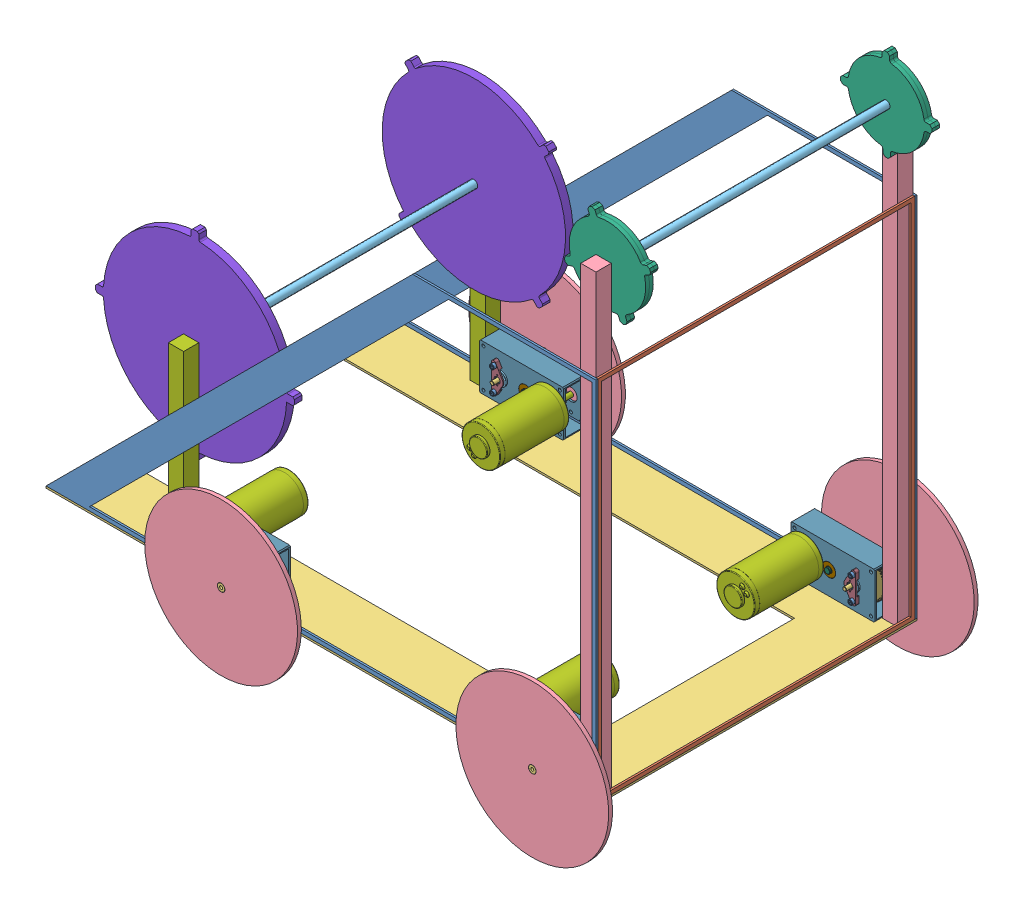
SolidWorks assembly catbot, configuration Default. Lengths in mm.
Overall size (1017.77 943.44 617.22).
104 component instances, 26 part files, 65 mates.
Components (placement in the parent):
- out frame-1: out frame [Default] at (-229.7492 222.8488 726.0954) size (914.4 609.6 3.17)
- out frame-2: out frame [Default] at (-229.7492 222.8488 1256.3204) size (914.4 609.6 3.17)
- front outer chassis-1: front outer chassis [Default] at (684.6508 527.6488 992.7954) x (0 0 1) z (-1 0 0) size (527.05 609.6 3.17)
- base plate-1: base plate [Default] at (227.4508 219.6738 992.7954) x (-1 0 0) z (0 0 -1) size (914.4 3.17 533.4)
- bar-1: bar [Default] at (644.4149 984.8488 731.8104) x (1 0 0) z (0 -1 0) size (25.4 25.4 762)
- bar-2: bar [Default] at (644.4149 222.8488 1253.7804) x (1 0 0) z (0 1 0) size (25.4 25.4 762)
- Toughbox Nano 500 key-1: Toughbox Nano 500 key [Default] at (-4.173 260.9488 745.1454) x (1 0 0) z (0 -1 0) size (155.61 199.38 84.31)
  - fr-6-zz-1: fr-6-zz [Default] at (44.2691 14.351 6.042) x (1 0 0) z (0 1 0) size (24.69 24.69 7.16)
  - fr8zz-hex-1: fr8zz-hex [Default] at (35.4076 -22.2783 0) x (0.98361 0 -0.180311) z (0 1 0) size (31.12 31.12 7.93)
  - CIM motor-1: CIM motor [Default] at (226.1362 38.1 -35.56) x (0 0 1) z (0 -1 0) size (64.01 64.01 154.95)
  - fr-6-zz-hex-1: fr-6-zz-hex [Default] at (84.883 -14.351 -6.1894) x (0.99986 0 -0.016728) z (0 -1 0) size (24.69 24.69 7.75)
  - fr-6-1: fr-6 [Default] at (86.7029 13.5128 -1.7646) x (0.722285 0 -0.691595) z (0 1 0) size (24.69 24.69 5.54)
  - Toughbox_d05-1: Toughbox_d05 [Default] at (76.1238 3.3528 0) x (-0.016728 0 -0.99986) z (0 1 0) size (65.97 66.04 10.34)
  - Toughbox_d08-1: Toughbox_d08 [Default] at (76.1238 3.3528 0) x (0.874268 0 0.485443) z (0 -1 0) size (20.03 20.32 15.25)
  - Toughbox_d06-1: Toughbox_d06 [Default] at (35.4076 -0.4318 0) x (0.335651 0 -0.941987) z (0 -1 0) size (65.97 66.04 10.62)
  - Toughbox_d29a-1: Toughbox_d29a [Default] at (35.3949 19.05 0) size (19.05 6.1 50.8)
  - Toughbox-nano-d01-1: Toughbox-nano-d01 [Default] at origin size (139.7 38.1 76.2)
  - Toughbox-nano-d02-1: Toughbox-nano-d02 [Default] at (33.7409 -21.4122 -4.4704) x (-0.874268 0 -0.485443) z (-0.485443 0 0.874268) size (11 43.81 9.52)
  - Toughbox_d09-1: Toughbox_d09 [Default] at (116.84 1.524 0) x (-1 0 0) z (0 1 0) size (20.03 20.32 12.7)
  - 8mm_spring_clip-1: 8mm_spring_clip [Default] at (116.84 0.5836 0) x (0 1 0) z (0.466354 0 -0.884598) size (1.12 14.83 14.83)
  - 2mmx2mmx10mm_key-1: 2mmx2mmx10mm_key [Default] at (119.2442 -2.476 4.8) x (0 1 0) z (1 0 0) size (10 2 2)
  - 10-32x0500_shcs-1: 10-32x0500_shcs [Default] at (30.6324 29.9212 19.05) x (0.282005 0 -0.959413) z (0.959413 0 0.282005) size (7.82 17.48 7.82)
  - 10-32x0500_shcs-2: 10-32x0500_shcs [Default] at (30.6324 29.9212 -19.05) x (0.282005 0 -0.959413) z (0.959413 0 0.282005) size (7.82 17.48 7.82)
  - 10-32x0500_shcs-3: 10-32x0500_shcs [Default] at (116.84 11.0998 -25.4) x (-0.525528 0 0.850777) z (0.850777 0 0.525528) size (7.82 17.48 7.82)
  - 10-32x0500_shcs-4: 10-32x0500_shcs [Default] at (116.84 11.0998 25.4) x (-0.525528 0 0.850777) z (0.850777 0 0.525528) size (7.82 17.48 7.82)
  - 500-e-klip-1: 500-e-klip [Default] at (35.4076 0.8382 0) x (-0.210896 0 -0.977509) z (0 -1 0) size (19.07 20.96 1.27)
  - Toughbox-nano-d04-1: Toughbox-nano-d04 [Default] at (-2.1102 -22.352 -18.3768) x (-0.647959 0 -0.761675) z (-0.761675 0 0.647959) size (14.66 95.12 12.7)
- Toughbox Nano 500 key-2: Toughbox Nano 500 key [Default] at (135.527 260.9488 1237.2704) x (-1 0 0) z (0 -1 0) size (155.61 199.38 84.31)
  - fr-6-zz-1: fr-6-zz [Default] at (44.2691 14.351 6.042) x (1 0 0) z (0 1 0) size (24.69 24.69 7.16)
  - fr8zz-hex-1: fr8zz-hex [Default] at (35.4076 -22.2783 0) x (0.98361 0 -0.180311) z (0 1 0) size (31.12 31.12 7.93)
  - CIM motor-1: CIM motor [Default] at (226.1362 38.1 -35.56) x (0 0 1) z (0 -1 0) size (64.01 64.01 154.95)
  - fr-6-zz-hex-1: fr-6-zz-hex [Default] at (84.883 -14.351 -6.1894) x (0.99986 0 -0.016728) z (0 -1 0) size (24.69 24.69 7.75)
  - fr-6-1: fr-6 [Default] at (86.7029 13.5128 -1.7646) x (0.722285 0 -0.691595) z (0 1 0) size (24.69 24.69 5.54)
  - Toughbox_d05-1: Toughbox_d05 [Default] at (76.1238 3.3528 0) x (-0.016728 0 -0.99986) z (0 1 0) size (65.97 66.04 10.34)
  - Toughbox_d08-1: Toughbox_d08 [Default] at (76.1238 3.3528 0) x (0.874268 0 0.485443) z (0 -1 0) size (20.03 20.32 15.25)
  - Toughbox_d06-1: Toughbox_d06 [Default] at (35.4076 -0.4318 0) x (0.335651 0 -0.941987) z (0 -1 0) size (65.97 66.04 10.62)
  - Toughbox_d29a-1: Toughbox_d29a [Default] at (35.3949 19.05 0) size (19.05 6.1 50.8)
  - Toughbox-nano-d01-1: Toughbox-nano-d01 [Default] at origin size (139.7 38.1 76.2)
  - Toughbox-nano-d02-1: Toughbox-nano-d02 [Default] at (33.7409 -21.4122 -4.4704) x (-0.874268 0 -0.485443) z (-0.485443 0 0.874268) size (11 43.81 9.52)
  - Toughbox_d09-1: Toughbox_d09 [Default] at (116.84 1.524 0) x (-1 0 0) z (0 1 0) size (20.03 20.32 12.7)
  - 8mm_spring_clip-1: 8mm_spring_clip [Default] at (116.84 0.5836 0) x (0 1 0) z (0.466354 0 -0.884598) size (1.12 14.83 14.83)
  - 2mmx2mmx10mm_key-1: 2mmx2mmx10mm_key [Default] at (119.2442 -2.476 4.8) x (0 1 0) z (1 0 0) size (10 2 2)
  - 10-32x0500_shcs-1: 10-32x0500_shcs [Default] at (30.6324 29.9212 19.05) x (0.282005 0 -0.959413) z (0.959413 0 0.282005) size (7.82 17.48 7.82)
  - 10-32x0500_shcs-2: 10-32x0500_shcs [Default] at (30.6324 29.9212 -19.05) x (0.282005 0 -0.959413) z (0.959413 0 0.282005) size (7.82 17.48 7.82)
  - 10-32x0500_shcs-3: 10-32x0500_shcs [Default] at (116.84 11.0998 -25.4) x (-0.525528 0 0.850777) z (0.850777 0 0.525528) size (7.82 17.48 7.82)
  - 10-32x0500_shcs-4: 10-32x0500_shcs [Default] at (116.84 11.0998 25.4) x (-0.525528 0 0.850777) z (0.850777 0 0.525528) size (7.82 17.48 7.82)
  - 500-e-klip-1: 500-e-klip [Default] at (35.4076 0.8382 0) x (-0.210896 0 -0.977509) z (0 -1 0) size (19.07 20.96 1.27)
  - Toughbox-nano-d04-1: Toughbox-nano-d04 [Default] at (-2.1102 -22.352 -18.3768) x (-0.647959 0 -0.761675) z (-0.761675 0 0.647959) size (14.66 95.12 12.7)
- Toughbox Nano 500 key-3: Toughbox Nano 500 key [Default] at (656.0758 260.9488 1240.4454) x (-1 0 0) z (0 -1 0) size (155.61 199.38 84.31)
  - fr-6-zz-1: fr-6-zz [Default] at (44.2691 14.351 6.042) x (1 0 0) z (0 1 0) size (24.69 24.69 7.16)
  - fr8zz-hex-1: fr8zz-hex [Default] at (35.4076 -22.2783 0) x (0.98361 0 -0.180311) z (0 1 0) size (31.12 31.12 7.93)
  - CIM motor-1: CIM motor [Default] at (226.1362 38.1 -35.56) x (0 0 1) z (0 -1 0) size (64.01 64.01 154.95)
  - fr-6-zz-hex-1: fr-6-zz-hex [Default] at (84.883 -14.351 -6.1894) x (0.99986 0 -0.016728) z (0 -1 0) size (24.69 24.69 7.75)
  - fr-6-1: fr-6 [Default] at (86.7029 13.5128 -1.7646) x (0.722285 0 -0.691595) z (0 1 0) size (24.69 24.69 5.54)
  - Toughbox_d05-1: Toughbox_d05 [Default] at (76.1238 3.3528 0) x (-0.016728 0 -0.99986) z (0 1 0) size (65.97 66.04 10.34)
  - Toughbox_d08-1: Toughbox_d08 [Default] at (76.1238 3.3528 0) x (0.874268 0 0.485443) z (0 -1 0) size (20.03 20.32 15.25)
  - Toughbox_d06-1: Toughbox_d06 [Default] at (35.4076 -0.4318 0) x (0.335651 0 -0.941987) z (0 -1 0) size (65.97 66.04 10.62)
  - Toughbox_d29a-1: Toughbox_d29a [Default] at (35.3949 19.05 0) size (19.05 6.1 50.8)
  - Toughbox-nano-d01-1: Toughbox-nano-d01 [Default] at origin size (139.7 38.1 76.2)
  - Toughbox-nano-d02-1: Toughbox-nano-d02 [Default] at (33.7409 -21.4122 -4.4704) x (-0.874268 0 -0.485443) z (-0.485443 0 0.874268) size (11 43.81 9.52)
  - Toughbox_d09-1: Toughbox_d09 [Default] at (116.84 1.524 0) x (-1 0 0) z (0 1 0) size (20.03 20.32 12.7)
  - 8mm_spring_clip-1: 8mm_spring_clip [Default] at (116.84 0.5836 0) x (0 1 0) z (0.466354 0 -0.884598) size (1.12 14.83 14.83)
  - 2mmx2mmx10mm_key-1: 2mmx2mmx10mm_key [Default] at (119.2442 -2.476 4.8) x (0 1 0) z (1 0 0) size (10 2 2)
  - 10-32x0500_shcs-1: 10-32x0500_shcs [Default] at (30.6324 29.9212 19.05) x (0.282005 0 -0.959413) z (0.959413 0 0.282005) size (7.82 17.48 7.82)
  - 10-32x0500_shcs-2: 10-32x0500_shcs [Default] at (30.6324 29.9212 -19.05) x (0.282005 0 -0.959413) z (0.959413 0 0.282005) size (7.82 17.48 7.82)
  - 10-32x0500_shcs-3: 10-32x0500_shcs [Default] at (116.84 11.0998 -25.4) x (-0.525528 0 0.850777) z (0.850777 0 0.525528) size (7.82 17.48 7.82)
  - 10-32x0500_shcs-4: 10-32x0500_shcs [Default] at (116.84 11.0998 25.4) x (-0.525528 0 0.850777) z (0.850777 0 0.525528) size (7.82 17.48 7.82)
  - 500-e-klip-1: 500-e-klip [Default] at (35.4076 0.8382 0) x (-0.210896 0 -0.977509) z (0 -1 0) size (19.07 20.96 1.27)
  - Toughbox-nano-d04-1: Toughbox-nano-d04 [Default] at (-2.1102 -22.352 -18.3768) x (-0.647959 0 -0.761675) z (-0.761675 0 0.647959) size (14.66 95.12 12.7)
- Toughbox Nano 500 key-4: Toughbox Nano 500 key [Default] at (656.0758 260.9488 748.3204) x (-1 0 0) z (0 1 0) size (155.61 199.38 84.31)
  - fr-6-zz-1: fr-6-zz [Default] at (44.2691 14.351 6.042) x (1 0 0) z (0 1 0) size (24.69 24.69 7.16)
  - fr8zz-hex-1: fr8zz-hex [Default] at (35.4076 -22.2783 0) x (0.98361 0 -0.180311) z (0 1 0) size (31.12 31.12 7.93)
  - CIM motor-1: CIM motor [Default] at (226.1362 38.1 -35.56) x (0 0 1) z (0 -1 0) size (64.01 64.01 154.95)
  - fr-6-zz-hex-1: fr-6-zz-hex [Default] at (84.883 -14.351 -6.1894) x (0.99986 0 -0.016728) z (0 -1 0) size (24.69 24.69 7.75)
  - fr-6-1: fr-6 [Default] at (86.7029 13.5128 -1.7646) x (0.722285 0 -0.691595) z (0 1 0) size (24.69 24.69 5.54)
  - Toughbox_d05-1: Toughbox_d05 [Default] at (76.1238 3.3528 0) x (-0.016728 0 -0.99986) z (0 1 0) size (65.97 66.04 10.34)
  - Toughbox_d08-1: Toughbox_d08 [Default] at (76.1238 3.3528 0) x (0.874268 0 0.485443) z (0 -1 0) size (20.03 20.32 15.25)
  - Toughbox_d06-1: Toughbox_d06 [Default] at (35.4076 -0.4318 0) x (0.335651 0 -0.941987) z (0 -1 0) size (65.97 66.04 10.62)
  - Toughbox_d29a-1: Toughbox_d29a [Default] at (35.3949 19.05 0) size (19.05 6.1 50.8)
  - Toughbox-nano-d01-1: Toughbox-nano-d01 [Default] at origin size (139.7 38.1 76.2)
  - Toughbox-nano-d02-1: Toughbox-nano-d02 [Default] at (33.7409 -21.4122 -4.4704) x (-0.874268 0 -0.485443) z (-0.485443 0 0.874268) size (11 43.81 9.52)
  - Toughbox_d09-1: Toughbox_d09 [Default] at (116.84 1.524 0) x (-1 0 0) z (0 1 0) size (20.03 20.32 12.7)
  - 8mm_spring_clip-1: 8mm_spring_clip [Default] at (116.84 0.5836 0) x (0 1 0) z (0.466354 0 -0.884598) size (1.12 14.83 14.83)
  - 2mmx2mmx10mm_key-1: 2mmx2mmx10mm_key [Default] at (119.2442 -2.476 4.8) x (0 1 0) z (1 0 0) size (10 2 2)
  - 10-32x0500_shcs-1: 10-32x0500_shcs [Default] at (30.6324 29.9212 19.05) x (0.282005 0 -0.959413) z (0.959413 0 0.282005) size (7.82 17.48 7.82)
  - 10-32x0500_shcs-2: 10-32x0500_shcs [Default] at (30.6324 29.9212 -19.05) x (0.282005 0 -0.959413) z (0.959413 0 0.282005) size (7.82 17.48 7.82)
  - 10-32x0500_shcs-3: 10-32x0500_shcs [Default] at (116.84 11.0998 -25.4) x (-0.525528 0 0.850777) z (0.850777 0 0.525528) size (7.82 17.48 7.82)
  - 10-32x0500_shcs-4: 10-32x0500_shcs [Default] at (116.84 11.0998 25.4) x (-0.525528 0 0.850777) z (0.850777 0 0.525528) size (7.82 17.48 7.82)
  - 500-e-klip-1: 500-e-klip [Default] at (35.4076 0.8382 0) x (-0.210896 0 -0.977509) z (0 -1 0) size (19.07 20.96 1.27)
  - Toughbox-nano-d04-1: Toughbox-nano-d04 [Default] at (-2.1102 -22.352 -18.3768) x (-0.647959 0 -0.761675) z (-0.761675 0 0.647959) size (14.66 95.12 12.7)
- wheel-1: wheel [Default] at (100.1194 260.9488 1291.8804) size (254 254 6.35)
- wheel-2: wheel [Default] at (620.6682 260.9488 687.3604) size (254 254 6.35)
- wheel-3: wheel [Default] at (620.6682 260.9488 1295.0554) size (254 254 6.35)
- wheel-4: wheel [Default] at (31.2346 260.9488 684.1854) size (254 254 6.35)
- rod-1: rod [Default] at (675.1258 978.4988 761.0204) x (-0.908266 0.418392 0) z (0.418392 0.908266 0) size (12.7 469.9 12.7)
- gear top-1: gear top [Default] at (675.1258 978.4988 1224.5704) x (-0.929856 -0.367924 0) z (-0.367924 0.929856 0) size (152.4 6.35 152.4)
- gear top-2: gear top [Default] at (675.1258 978.4988 754.6704) x (0.999956 0.009345 0) z (0.009345 -0.999956 0) size (152.4 6.35 152.4)
- gear top-3: gear top [Default] at (675.1258 978.4988 1218.2204) x (-0.929856 -0.367924 0) z (-0.367924 0.929856 0) size (152.4 6.35 152.4)
- gear top-4: gear top [Default] at (675.1258 978.4988 761.0204) x (0.999956 0.009345 0) z (0.009345 -0.999956 0) size (152.4 6.35 152.4)
- short rod-1: short rod [Default] at (-16.873 527.6488 741.9704) x (0 0 -1) z (0 -1 0) size (25.4 25.4 304.8)
- short rod-2: short rod [Default] at (-16.873 527.6488 1243.6204) x (1 0 0) z (0 -1 0) size (25.4 25.4 304.8)
- rod-2: rod [Default] at (-10.523 521.2988 1224.5704) x (-0.476529 0.879159 0) z (-0.879159 -0.476529 0) size (12.7 469.9 12.7)
- big gear-1: big gear [Default] at (-10.523 521.2988 754.6704) x (-0.739218 -0.673466 0) z (0 0 1) size (330.2 330.2 12.7)
- big gear-2: big gear [Default] at (-10.523 521.2988 1218.2204) size (330.2 330.2 12.7)
Mates (geometry in assembly coordinates):
- Coincident1: coincident anti-aligned: plane of out frame-2 through (-229.7492 222.8488 1256.3204) normal (0 0 -1); plane of front outer chassis-1 through (681.4758 222.8488 1256.3204) normal (0 0 1)
- Coincident2: coincident aligned: plane of out frame-2 through (684.6508 832.4488 1259.4954) normal (0 1 0); plane of front outer chassis-1 through (681.4758 832.4488 729.2704) normal (0 1 0)
- Coincident3: coincident aligned: plane of out frame-2 through (684.6508 222.8488 1259.4954) normal (1 0 0); plane of front outer chassis-1 through (684.6508 527.6488 992.7954) normal (1 0 0)
- Coincident4: coincident anti-aligned: plane of out frame-1 through (-229.7492 222.8488 729.2704) normal (0 0 1); plane of front outer chassis-1 through (681.4758 222.8488 729.2704) normal (0 0 -1)
- Coincident5: coincident aligned: plane of out frame-1 through (684.6508 832.4488 729.2704) normal (0 1 0); plane of front outer chassis-1 through (681.4758 832.4488 729.2704) normal (0 1 0)
- Coincident6: coincident aligned: plane of out frame-1 through (684.6508 222.8488 729.2704) normal (1 0 0); plane of front outer chassis-1 through (684.6508 527.6488 992.7954) normal (1 0 0)
- Coincident7: coincident aligned: plane of front outer chassis-1 through (684.6508 527.6488 992.7954) normal (1 0 0); plane of base plate-1 through (684.6508 222.8488 726.0954) normal (1 0 0)
- Coincident8: coincident aligned: plane of out frame-1 through (-229.7492 222.8488 726.0954) normal (0 0 -1); plane of base plate-1 through (684.6508 222.8488 726.0954) normal (0 0 -1)
- Coincident9: coincident anti-aligned: plane of out frame-1 through (-229.7492 222.8488 729.2704) normal (0 -1 0); plane of base plate-1 through (227.4508 222.8488 992.7954) normal (0 1 0)
- Coincident11: coincident anti-aligned: plane of base plate-1 through (227.4508 222.8488 992.7954) normal (0 1 0); plane of bar-2 through (644.4149 222.8488 1253.7804) normal (0 -1 0)
- Coincident12: coincident anti-aligned: plane of front outer chassis-1 through (681.4758 527.6488 992.7954) normal (-1 0 0); plane of bar-2 through (681.4758 984.8488 1230.9204) normal (1 0 0)
- Coincident13: coincident anti-aligned: plane of out frame-2 through (-229.7492 222.8488 1256.3204) normal (0 0 -1); plane of bar-2 through (681.4758 984.8488 1256.3204) normal (0 0 1)
- Coincident14: coincident anti-aligned: plane of base plate-1 through (227.4508 222.8488 992.7954) normal (0 1 0); plane of bar-1 through (644.4149 222.8488 731.8104) normal (0 -1 0)
- Coincident15: coincident anti-aligned: plane of out frame-1 through (-229.7492 222.8488 729.2704) normal (0 0 1); plane of bar-1 through (681.4758 222.8488 729.2704) normal (0 0 -1)
- Coincident16: coincident anti-aligned: plane of front outer chassis-1 through (681.4758 527.6488 992.7954) normal (-1 0 0); plane of bar-1 through (681.4758 222.8488 754.6704) normal (1 0 0)
- Coincident17: coincident anti-aligned: plane of base plate-1 through (227.4508 222.8488 992.7954) normal (0 1 0); plane of Toughbox Nano 500 key-4/Toughbox-nano-d01-1 through (516.3758 222.8488 767.3704) normal (0 -1 0)
- Coincident18: coincident anti-aligned: plane of base plate-1 through (227.4508 222.8488 992.7954) normal (0 1 0); plane of Toughbox Nano 500 key-3/Toughbox-nano-d01-1 through (516.3758 222.8488 1259.4954) normal (0 -1 0)
- Coincident19: coincident anti-aligned: plane of base plate-1 through (227.4508 222.8488 992.7954) normal (0 1 0); plane of Toughbox Nano 500 key-1/Toughbox-nano-d01-1 through (135.527 222.8488 726.0954) normal (0 -1 0)
- Coincident20: coincident anti-aligned: plane of base plate-1 through (227.4508 222.8488 992.7954) normal (0 1 0); plane of Toughbox Nano 500 key-2/Toughbox-nano-d01-1 through (-4.173 222.8488 1256.3204) normal (0 -1 0)
- Coincident21: coincident anti-aligned: plane of out frame-1 through (-229.7492 222.8488 729.2704) normal (0 0 1); plane of Toughbox Nano 500 key-4/Toughbox-nano-d01-1 through (516.3758 222.8488 729.2704) normal (0 0 -1)
- Coincident22: coincident anti-aligned: plane of bar-1 through (656.0758 222.8488 754.6704) normal (-1 0 0); plane of Toughbox Nano 500 key-4/Toughbox-nano-d01-1 through (656.0758 299.0488 729.2704) normal (1 0 0)
- Coincident23: coincident aligned: plane of out frame-1 through (-229.7492 222.8488 726.0954) normal (0 0 -1); plane of Toughbox Nano 500 key-1/Toughbox-nano-d01-1 through (135.527 299.0488 726.0954) normal (0 0 -1)
- Parallel1: parallel anti-aligned: plane of Toughbox Nano 500 key-3/Toughbox-nano-d01-1 through (516.3758 299.0488 1259.4954) normal (0 0 1); plane of bar-2 through (681.4758 984.8488 1230.9204) normal (0 0 -1)
- Coincident25: coincident aligned: plane of out frame-2 through (-229.7492 222.8488 1259.4954) normal (0 0 1); plane of Toughbox Nano 500 key-3/Toughbox-nano-d01-1 through (516.3758 299.0488 1259.4954) normal (0 0 1)
- Coincident26: coincident anti-aligned: plane of bar-2 through (656.0758 984.8488 1230.9204) normal (-1 0 0); plane of Toughbox Nano 500 key-3/Toughbox-nano-d01-1 through (656.0758 222.8488 1259.4954) normal (1 0 0)
- Coincident27: coincident anti-aligned: plane of out frame-2 through (-229.7492 222.8488 1256.3204) normal (0 0 -1); plane of Toughbox Nano 500 key-2/Toughbox-nano-d01-1 through (-4.173 299.0488 1256.3204) normal (0 0 1)
- Coincident28: coincident aligned: plane of Toughbox Nano 500 key-1/Toughbox-nano-d01-1 through (-4.173 222.8488 726.0954) normal (-1 0 0); plane of Toughbox Nano 500 key-2/Toughbox-nano-d01-1 through (-4.173 222.8488 1256.3204) normal (-1 0 0)
- Concentric1: concentric anti-aligned: cylinder of Toughbox Nano 500 key-1/Toughbox-nano-d04-1 through (31.2346 260.9488 684.1854) axis (0 0 -1) radius 6.3373; cylinder of wheel-4 through (31.2346 260.9488 684.1854) axis (0 0 1) radius 6.35
- Coincident29: coincident aligned: plane of Toughbox Nano 500 key-1/Toughbox-nano-d04-1 through (31.2346 260.9488 684.1854) normal (0 0 -1); plane of wheel-4 through (31.2346 260.9488 684.1854) normal (0 0 -1)
- Coincident30: coincident aligned: plane of Toughbox Nano 500 key-4/Toughbox-nano-d04-1 through (620.6682 260.9488 687.3604) normal (0 0 -1); plane of wheel-2 through (620.6682 260.9488 687.3604) normal (0 0 -1)
- Concentric2: concentric anti-aligned: cylinder of Toughbox Nano 500 key-4/Toughbox-nano-d04-1 through (620.6682 260.9488 687.3604) axis (0 0 -1) radius 6.3373; cylinder of wheel-2 through (620.6682 260.9488 687.3604) axis (0 0 1) radius 6.35
- Coincident31: coincident aligned: plane of Toughbox Nano 500 key-2/Toughbox-nano-d04-1 through (100.1194 260.9488 1298.2304) normal (0 0 1); plane of wheel-1 through (100.1194 260.9488 1298.2304) normal (0 0 1)
- Concentric3: concentric aligned: cylinder of Toughbox Nano 500 key-2/Toughbox-nano-d04-1 through (100.1194 260.9488 1298.2304) axis (0 0 1) radius 6.3373; cylinder of wheel-1 through (100.1194 260.9488 1291.8804) axis (0 0 1) radius 6.35
- Coincident32: coincident aligned: plane of Toughbox Nano 500 key-3/Toughbox-nano-d04-1 through (620.6682 260.9488 1301.4054) normal (0 0 1); plane of wheel-3 through (620.6682 260.9488 1301.4054) normal (0 0 1)
- Concentric4: concentric aligned: cylinder of Toughbox Nano 500 key-3/Toughbox-nano-d04-1 through (620.6682 260.9488 1301.4054) axis (0 0 1) radius 6.3373; cylinder of wheel-3 through (620.6682 260.9488 1295.0554) axis (0 0 1) radius 6.35
- Coincident33: coincident anti-aligned: plane of bar-2 through (681.4758 984.8488 1230.9204) normal (0 0 -1); plane of rod-1 through (675.1258 978.4988 1230.9204) normal (0 0 1)
- Concentric5: concentric anti-aligned: cylinder of rod-1 through (675.1258 978.4988 1230.9204) axis (0 0 -1) radius 6.35; cylinder of gear top-1 through (675.1258 978.4988 1224.5704) axis (0 0 1) radius 3.175
- Concentric6: concentric anti-aligned: cylinder of rod-1 through (675.1258 978.4988 1230.9204) axis (0 0 -1) radius 6.35; cylinder of gear top-2 through (675.1258 978.4988 754.6704) axis (0 0 1) radius 3.175
- Tangent2: tangent aligned: plane of bar-2 through (644.4149 984.8488 1253.7804) normal (0 1 0); cylinder of rod-1 through (675.1258 978.4988 1230.9204) axis (0 0 -1) radius 6.35
- Tangent4: tangent aligned: plane of bar-2 through (644.4149 984.8488 1253.7804) normal (0 1 0); cylinder of rod-1 through (675.1258 978.4988 1230.9204) axis (0 0 -1) radius 6.35
- Tangent5: tangent aligned: plane of bar-2 through (644.4149 984.8488 1253.7804) normal (0 1 0); cylinder of rod-1 through (675.1258 978.4988 1230.9204) axis (0 0 -1) radius 6.35
- Tangent6: tangent aligned: plane of bar-2 through (681.4758 984.8488 1230.9204) normal (1 0 0); cylinder of rod-1 through (675.1258 978.4988 1230.9204) axis (0 0 -1) radius 6.35
- Coincident34: coincident anti-aligned: plane of bar-2 through (681.4758 984.8488 1230.9204) normal (0 0 -1); plane of gear top-1 through (675.1258 978.4988 1230.9204) normal (0 0 1)
- Coincident35: coincident anti-aligned: plane of bar-1 through (681.4758 222.8488 754.6704) normal (0 0 1); plane of gear top-2 through (675.1258 978.4988 754.6704) normal (0 0 -1)
- Concentric7: concentric anti-aligned: cylinder of rod-1 through (675.1258 978.4988 1230.9204) axis (0 0 -1) radius 6.35; cylinder of gear top-4 through (675.1258 978.4988 761.0204) axis (0 0 1) radius 3.175
- Concentric9: concentric anti-aligned: cylinder of rod-1 through (675.1258 978.4988 1230.9204) axis (0 0 -1) radius 6.35; cylinder of gear top-3 through (675.1258 978.4988 1218.2204) axis (0 0 1) radius 3.175
- Coincident36: coincident anti-aligned: plane of gear top-1 through (675.1258 978.4988 1224.5704) normal (0 0 -1); plane of gear top-3 through (675.1258 978.4988 1224.5704) normal (0 0 1)
- Coincident37: coincident anti-aligned: plane of gear top-2 through (675.1258 978.4988 761.0204) normal (0 0 1); plane of gear top-4 through (675.1258 978.4988 761.0204) normal (0 0 -1)
- Concentric10: concentric aligned: cylinder of gear top-1 through (675.1258 978.4988 1230.9204) axis (0 0 -1) radius 63.5; cylinder of gear top-3 through (675.1258 978.4988 1224.5704) axis (0 0 -1) radius 63.5
- Coincident38: coincident aligned: plane of gear top-1 through (697.257 905.3075 1230.9204) normal (0.367924 -0.929856 0); plane of gear top-3 through (697.257 905.3075 1224.5704) normal (0.367924 -0.929856 0)
- Concentric11: concentric aligned: cylinder of gear top-2 through (675.1258 978.4988 761.0204) axis (0 0 -1) radius 63.5; cylinder of gear top-4 through (675.1258 978.4988 767.3704) axis (0 0 -1) radius 63.5
- Coincident39: coincident aligned: plane of gear top-2 through (680.7634 1054.7548 761.0204) normal (-0.009345 0.999956 0); plane of gear top-4 through (680.7634 1054.7548 767.3704) normal (-0.009345 0.999956 0)
- Coincident40: coincident anti-aligned: plane of base plate-1 through (227.4508 222.8488 992.7954) normal (0 1 0); plane of short rod-2 through (-16.873 222.8488 1243.6204) normal (0 -1 0)
- Coincident41: coincident anti-aligned: plane of base plate-1 through (227.4508 222.8488 992.7954) normal (0 1 0); plane of short rod-1 through (-16.873 222.8488 741.9704) normal (0 -1 0)
- Coincident42: coincident anti-aligned: plane of out frame-2 through (-229.7492 222.8488 1256.3204) normal (0 0 -1); plane of short rod-2 through (-29.573 222.8488 1256.3204) normal (0 0 1)
- Coincident43: coincident anti-aligned: plane of out frame-1 through (-229.7492 222.8488 729.2704) normal (0 0 1); plane of short rod-1 through (-29.573 222.8488 729.2704) normal (0 0 -1)
- Coincident44: coincident anti-aligned: plane of Toughbox Nano 500 key-1/Toughbox-nano-d01-1 through (-4.173 222.8488 726.0954) normal (-1 0 0); plane of short rod-1 through (-4.173 222.8488 754.6704) normal (1 0 0)
- Coincident45: coincident anti-aligned: plane of Toughbox Nano 500 key-2/Toughbox-nano-d01-1 through (-4.173 222.8488 1256.3204) normal (-1 0 0); plane of short rod-2 through (-4.173 222.8488 1230.9204) normal (1 0 0)
- Coincident46: coincident anti-aligned: plane of short rod-1 through (-29.573 222.8488 754.6704) normal (0 0 1); plane of rod-2 through (-10.523 521.2988 754.6704) normal (0 0 -1)
- Tangent7: tangent aligned: plane of short rod-1 through (-16.873 527.6488 741.9704) normal (0 1 0); cylinder of rod-2 through (-10.523 521.2988 754.6704) axis (0 0 1) radius 6.35
- Tangent8: tangent aligned: plane of short rod-1 through (-4.173 222.8488 754.6704) normal (1 0 0); cylinder of rod-2 through (-10.523 521.2988 754.6704) axis (0 0 1) radius 6.35
- Coincident47: coincident anti-aligned: plane of short rod-1 through (-29.573 222.8488 754.6704) normal (0 0 1); plane of big gear-1 through (-10.523 521.2988 754.6704) normal (0 0 -1)
- Concentric12: concentric aligned: cylinder of rod-2 through (-10.523 521.2988 754.6704) axis (0 0 1) radius 6.35; cylinder of big gear-1 through (-10.523 521.2988 754.6704) axis (0 0 1) radius 6.35
- Coincident48: coincident anti-aligned: plane of short rod-2 through (-29.573 222.8488 1230.9204) normal (0 0 -1); plane of big gear-2 through (-10.523 521.2988 1230.9204) normal (0 0 1)
- Concentric13: concentric aligned: cylinder of rod-2 through (-10.523 521.2988 754.6704) axis (0 0 1) radius 6.35; cylinder of big gear-2 through (-10.523 521.2988 1218.2204) axis (0 0 1) radius 6.35
